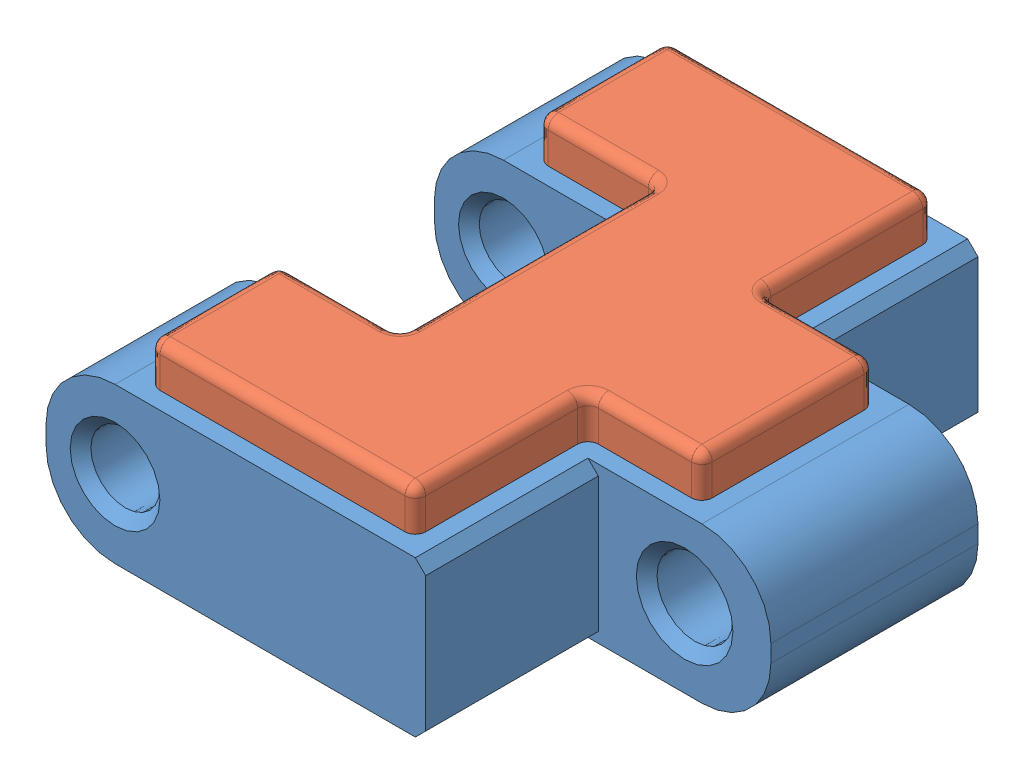
SolidWorks assembly bg_PipeMouse_KettenGliedGummi, configuration Standard. Lengths in mm.
Overall size (16 5.7 16).
2 component instances, 2 part files, 3 mates.
Components (placement in the parent):
- pipemouse_Kettenglied-1: pipemouse_Kettenglied [MoosV] at (-9.6091 -2.9927 16) size (16 4.5 16)
- pipemouse_GummiPlatte-1: pipemouse_GummiPlatte [Standard] at (-3.6091 2.7073 16) x (1 0 0) z (0 -1 0) size (11 15 2)
Mates (geometry in assembly coordinates):
- Deckungsgleich1: coincident anti-aligned: plane of pipemouse_Kettenglied-1 through (-9.6091 0.7073 16) normal (0 1 0); plane of pipemouse_GummiPlatte-1 through (-3.6091 0.7073 16) normal (0 -1 0)
- Breite1: width anti-aligned: plane of pipemouse_GummiPlatte-1 through (-7.1091 0.7073 23.5) normal (0 0 1); plane of pipemouse_Kettenglied-1 through (-7.1091 0.7073 8.5) normal (0 0 -1); plane of pipemouse_GummiPlatte-1 through (-7.1091 0.7073 23.5) normal (0 0 -1); plane of pipemouse_Kettenglied-1 through (0.5909 0.7073 8.5) normal (0 0 1)
- Breite2: width anti-aligned: plane of pipemouse_GummiPlatte-1 through (-7.1091 0.7073 12.25) normal (-1 0 0); plane of pipemouse_Kettenglied-1 through (3.8909 0.7073 18.5) normal (1 0 0); plane of pipemouse_GummiPlatte-1 through (-7.1091 0.7073 8.5) normal (1 0 0); plane of pipemouse_Kettenglied-1 through (3.8909 0.7073 18.5) normal (-1 0 0)
